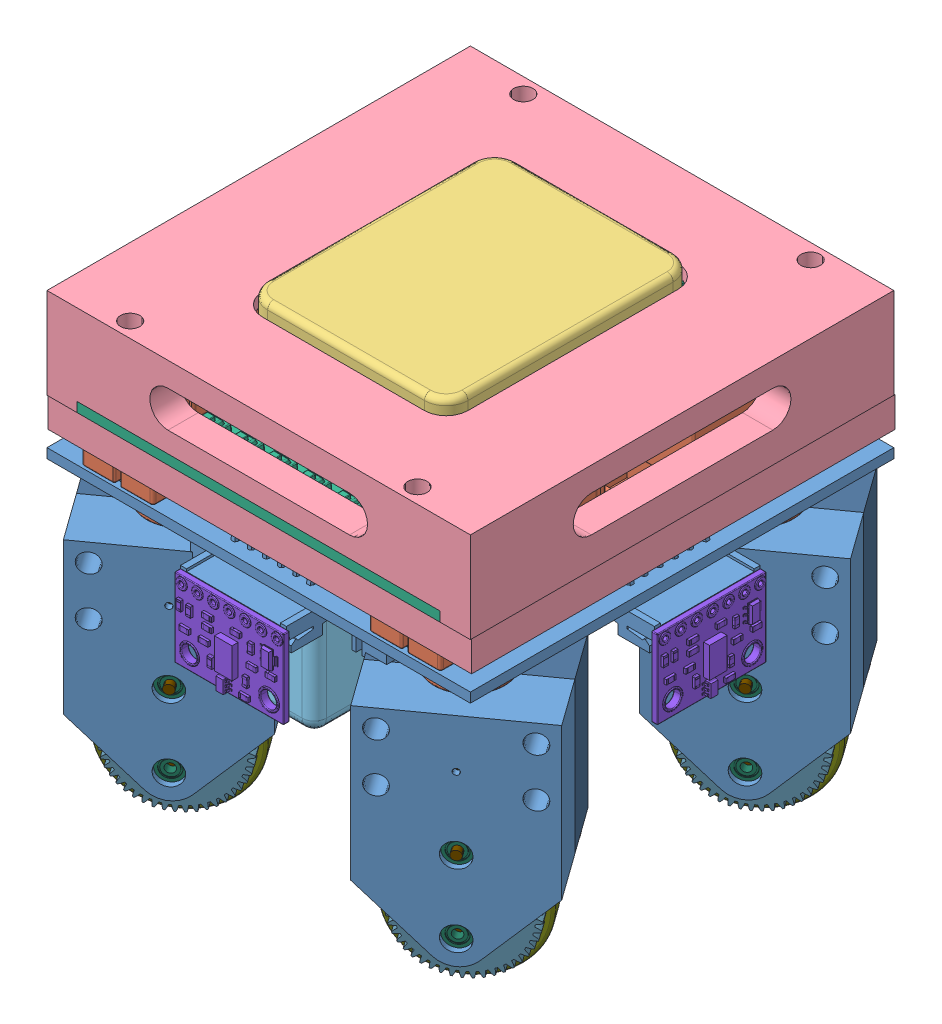
SolidWorks assembly Ver3, configuration Default. Lengths in mm.
Overall size (85.5 79.06 85.23).
91 component instances, 22 part files, 57 mates.
Components (placement in the parent):
- MicroMouse2023_T1-1: MicroMouse2023_T1 [Default] at (98.125 0 -88.375) x (-1 0 0) z (0 -1 0) size (78.34 78.34 13.7)
- Tower Pro MG90S Micro servo.step-1: Tower Pro MG90S Micro servo.step [Default] at (-23.75 9.625 18.55) x (0 0 1) z (1 0 0) size (32.2 32.25 12.33)
- Tower Pro MG90S Micro servo.step-2: Tower Pro MG90S Micro servo.step [Default] at (23.75 9.625 18.55) x (0 0 1) z (1 0 0) size (32.2 32.25 12.33)
- Tower Pro MG90S Micro servo.step-3: Tower Pro MG90S Micro servo.step [Default] at (23.75 9.625 -18.45) x (0 0 -1) z (-1 0 0) size (32.2 32.25 12.33)
- Tower Pro MG90S Micro servo.step-4: Tower Pro MG90S Micro servo.step [Default] at (-23.75 9.625 -18.45) x (0 0 -1) z (-1 0 0) size (32.2 32.25 12.33)
- HMI ESP-1: HMI ESP [Default] at (0 18.5 0) x (0 0 -1) z (1 0 0) size (41.13 12 33.13)
- Nap-1: Nap [Default] at (0 7.5 0) size (70 15 70)
- Pin-3: Pin [Default] at (0 -14.35 0.05) x (0 0 1) z (0 -1 0) size (62 10.5 18.5)
- MicroMouse2023_T2-1: MicroMouse2023_T2 [Default] at (-143.7625 7.5 -93.2) x (1 0 0) z (0 1 0) size (60 70 16.1)
- Ga Pin-1: Ga Pin [Default] at (0 -1.6 0.05) size (60 25 20)
- VL6180X-1: VL6180X [Default] at (-1.3897 -9.4497 22.1675) x (-1 0 0) z (0 0 1) size (18 13 2.15)
- VL6180X-2: VL6180X [Default] at (-22.1675 -9.4497 -1.3897) x (0 0 -1) z (-1 0 0) size (18 13 2.15)
- VL6180X-3: VL6180X [Default] at (1.8897 -9.4497 -22.1675) x (1 0 0) z (0 0 -1) size (18 13 2.15)
- VL6180X-4: VL6180X [Default] at (22.1675 -9.4497 1.8897) x (0 0 1) z (1 0 0) size (18 13 2.15)
- Cum banh _V3-1: Cum banh _V3 [Default] at (23.75 -7.9 23.925) x (0.599967 0 0.800025) z (-0.800025 0 0.599967) size (23.98 46.66 29.51)
  - N20 DC MOTOR Truc dai-1: N20 DC MOTOR Truc dai [Default] at (-12.2958 -8.0501 -0.3318) x (-0.02052 0 0.999789) z (0 1 0) size (12.48 22.6 10.65)
  - Vo SD2_V3-1: Vo SD2_V3 [Default] at (-9.498 -20 -0.1949) x (0.999789 0 0.02052) z (-0.02052 0 0.999789) size (9.5 35.95 25)
  - Nam cham-1: Nam cham [Default] at (-5.4362 -20 -0.5837) x (0.00804 0.92005 -0.39172) z (0.999789 0 0.02052) size (5 5 2)
  - Spur gear 0.4M 15T 1.0N-1: Spur gear 0.4M 15T 1.0N [Default] at (4.0008 -8.0501 0.0027) x (0.999789 0 0.02052) z (-0.020049 -0.213158 0.976812) size (2 6.74 6.78)
  - Banh rang T45-T15-1: Banh rang T45-T15 [Default] at (2.9736 -14.9168 -4.6144) x (0.999789 0 0.02052) z (0.003342 -0.986646 -0.162843) size (4 18.79 18.8)
    - Spur gear 0.4M 15T 1.5N-1: Spur gear 0.4M 15T 1.5N [Default] at (-0.8782 5.44 4.254) size (2 6.74 6.78)
    - Spur gear 0.4M 45T 1.5N-1: Spur gear 0.4M 45T 1.5N [Default] at (1.1218 5.44 4.254) size (2 18.79 18.8)
  - Vong bi 2x5x2.5-1: Vong bi 2x5x2.5 [Default] at (9.6072 -20 0.1972) x (0.020519 -0.01147 -0.999724) z (0.999789 0 0.02052) size (4 4 2)
  - Lop banh xe-1: Lop banh xe [Default] at (2.7494 -31.95 0.0564) x (-0.999789 0 -0.02052) z (0.012413 0.796313 -0.604757) size (4.5 21 21)
  - Mam banh xe-1: Mam banh xe [Default] at (0.4999 -31.95 0.0103) x (-0.999789 0 -0.02052) z (-0.016359 -0.603686 0.797054) size (2 15 15)
  - Spur gear 0.4M 45T 1.5N-1: Spur gear 0.4M 45T 1.5N [Default] at (3.9992 -31.95 0.0821) x (-0.999789 0 -0.02052) z (0.001118 0.998514 -0.054481) size (2 18.79 18.8)
  - Truc 2x20-2: Truc 2x20 [Default] at (0 -31.95 0) x (0.017704 -0.505658 -0.862552) z (0.999789 0 0.02052) size (1.5 1.5 14)
  - Vo SD1_V3-1: Vo SD1_V3 [Default] at (0 -20 0) x (0.999789 0 0.02052) z (-0.02052 0 0.999789) size (9.5 35.95 25)
  - Vong bi 2x5x2.5-2: Vong bi 2x5x2.5 [Default] at (-5.3897 -31.95 -0.1106) x (0.002111 0.994694 -0.102859) z (0.999789 0 0.02052) size (4 4 2)
  - Vong bi 2x5x2.5-3: Vong bi 2x5x2.5 [Default] at (9.6072 -31.95 0.1972) x (0.02052 0 -0.999789) z (0.999789 0 0.02052) size (4 4 2)
  - MT6701-1: MT6701 [Default] at (-11.0547 -20 -0.2269) x (0.02052 0 -0.999789) z (0.999789 0 0.02052) size (23 17 3.61)
  - Truc 2x20-3: Truc 2x20 [Default] at (2.5524 -20 0.0524) x (0.009005 -0.898579 -0.43872) z (0.999789 0 0.02052) size (1.5 1.5 14)
  - Ga nam chamV3-1: Ga nam chamV3 [Default] at (-2.4465 -20 -0.0502) x (-0.999789 0 -0.02052) z (0.019076 -0.368528 -0.929421) size (4 8 8)
- Cum banh _V3-2: Cum banh _V3 [Default] at (-23.75 -7.9 23.925) x (0.599967 0 0.800025) z (-0.800025 0 0.599967) size (23.98 46.66 29.51)
  - N20 DC MOTOR Truc dai-1: N20 DC MOTOR Truc dai [Default] at (-12.2958 -8.0501 -0.3318) x (-0.02052 0 0.999789) z (0 1 0) size (12.48 22.6 10.65)
  - Vo SD2_V3-1: Vo SD2_V3 [Default] at (-9.498 -20 -0.1949) x (0.999789 0 0.02052) z (-0.02052 0 0.999789) size (9.5 35.95 25)
  - Nam cham-1: Nam cham [Default] at (-5.4362 -20 -0.5837) x (0.00804 0.92005 -0.39172) z (0.999789 0 0.02052) size (5 5 2)
  - Spur gear 0.4M 15T 1.0N-1: Spur gear 0.4M 15T 1.0N [Default] at (4.0008 -8.0501 0.0027) x (0.999789 0 0.02052) z (-0.020049 -0.213158 0.976812) size (2 6.74 6.78)
  - Banh rang T45-T15-1: Banh rang T45-T15 [Default] at (2.9736 -14.9168 -4.6144) x (0.999789 0 0.02052) z (0.003342 -0.986646 -0.162843) size (4 18.79 18.8)
    - Spur gear 0.4M 15T 1.5N-1: Spur gear 0.4M 15T 1.5N [Default] at (-0.8782 5.44 4.254) size (2 6.74 6.78)
    - Spur gear 0.4M 45T 1.5N-1: Spur gear 0.4M 45T 1.5N [Default] at (1.1218 5.44 4.254) size (2 18.79 18.8)
  - Vong bi 2x5x2.5-1: Vong bi 2x5x2.5 [Default] at (9.6072 -20 0.1972) x (0.020519 -0.01147 -0.999724) z (0.999789 0 0.02052) size (4 4 2)
  - Lop banh xe-1: Lop banh xe [Default] at (2.7494 -31.95 0.0564) x (-0.999789 0 -0.02052) z (0.012413 0.796313 -0.604757) size (4.5 21 21)
  - Mam banh xe-1: Mam banh xe [Default] at (0.4999 -31.95 0.0103) x (-0.999789 0 -0.02052) z (-0.016359 -0.603686 0.797054) size (2 15 15)
  - Spur gear 0.4M 45T 1.5N-1: Spur gear 0.4M 45T 1.5N [Default] at (3.9992 -31.95 0.0821) x (-0.999789 0 -0.02052) z (0.001118 0.998514 -0.054481) size (2 18.79 18.8)
  - Truc 2x20-2: Truc 2x20 [Default] at (0 -31.95 0) x (0.017704 -0.505658 -0.862552) z (0.999789 0 0.02052) size (1.5 1.5 14)
  - Vo SD1_V3-1: Vo SD1_V3 [Default] at (0 -20 0) x (0.999789 0 0.02052) z (-0.02052 0 0.999789) size (9.5 35.95 25)
  - Vong bi 2x5x2.5-2: Vong bi 2x5x2.5 [Default] at (-5.3897 -31.95 -0.1106) x (0.002111 0.994694 -0.102859) z (0.999789 0 0.02052) size (4 4 2)
  - Vong bi 2x5x2.5-3: Vong bi 2x5x2.5 [Default] at (9.6072 -31.95 0.1972) x (0.02052 0 -0.999789) z (0.999789 0 0.02052) size (4 4 2)
  - MT6701-1: MT6701 [Default] at (-11.0547 -20 -0.2269) x (0.02052 0 -0.999789) z (0.999789 0 0.02052) size (23 17 3.61)
  - Truc 2x20-3: Truc 2x20 [Default] at (2.5524 -20 0.0524) x (0.009005 -0.898579 -0.43872) z (0.999789 0 0.02052) size (1.5 1.5 14)
  - Ga nam chamV3-1: Ga nam chamV3 [Default] at (-2.4465 -20 -0.0502) x (-0.999789 0 -0.02052) z (0.019076 -0.368528 -0.929421) size (4 8 8)
- Cum banh _V3-3: Cum banh _V3 [Default] at (23.75 -7.9 -23.825) x (0.599967 0 0.800025) z (-0.800025 0 0.599967) size (23.98 46.66 29.51)
  - N20 DC MOTOR Truc dai-1: N20 DC MOTOR Truc dai [Default] at (-12.2958 -8.0501 -0.3318) x (-0.02052 0 0.999789) z (0 1 0) size (12.48 22.6 10.65)
  - Vo SD2_V3-1: Vo SD2_V3 [Default] at (-9.498 -20 -0.1949) x (0.999789 0 0.02052) z (-0.02052 0 0.999789) size (9.5 35.95 25)
  - Nam cham-1: Nam cham [Default] at (-5.4362 -20 -0.5837) x (0.00804 0.92005 -0.39172) z (0.999789 0 0.02052) size (5 5 2)
  - Spur gear 0.4M 15T 1.0N-1: Spur gear 0.4M 15T 1.0N [Default] at (4.0008 -8.0501 0.0027) x (0.999789 0 0.02052) z (-0.020049 -0.213158 0.976812) size (2 6.74 6.78)
  - Banh rang T45-T15-1: Banh rang T45-T15 [Default] at (2.9736 -14.9168 -4.6144) x (0.999789 0 0.02052) z (0.003342 -0.986646 -0.162843) size (4 18.79 18.8)
    - Spur gear 0.4M 15T 1.5N-1: Spur gear 0.4M 15T 1.5N [Default] at (-0.8782 5.44 4.254) size (2 6.74 6.78)
    - Spur gear 0.4M 45T 1.5N-1: Spur gear 0.4M 45T 1.5N [Default] at (1.1218 5.44 4.254) size (2 18.79 18.8)
  - Vong bi 2x5x2.5-1: Vong bi 2x5x2.5 [Default] at (9.6072 -20 0.1972) x (0.020519 -0.01147 -0.999724) z (0.999789 0 0.02052) size (4 4 2)
  - Lop banh xe-1: Lop banh xe [Default] at (2.7494 -31.95 0.0564) x (-0.999789 0 -0.02052) z (0.012413 0.796313 -0.604757) size (4.5 21 21)
  - Mam banh xe-1: Mam banh xe [Default] at (0.4999 -31.95 0.0103) x (-0.999789 0 -0.02052) z (-0.016359 -0.603686 0.797054) size (2 15 15)
  - Spur gear 0.4M 45T 1.5N-1: Spur gear 0.4M 45T 1.5N [Default] at (3.9992 -31.95 0.0821) x (-0.999789 0 -0.02052) z (0.001118 0.998514 -0.054481) size (2 18.79 18.8)
  - Truc 2x20-2: Truc 2x20 [Default] at (0 -31.95 0) x (0.017704 -0.505658 -0.862552) z (0.999789 0 0.02052) size (1.5 1.5 14)
  - Vo SD1_V3-1: Vo SD1_V3 [Default] at (0 -20 0) x (0.999789 0 0.02052) z (-0.02052 0 0.999789) size (9.5 35.95 25)
  - Vong bi 2x5x2.5-2: Vong bi 2x5x2.5 [Default] at (-5.3897 -31.95 -0.1106) x (0.002111 0.994694 -0.102859) z (0.999789 0 0.02052) size (4 4 2)
  - Vong bi 2x5x2.5-3: Vong bi 2x5x2.5 [Default] at (9.6072 -31.95 0.1972) x (0.02052 0 -0.999789) z (0.999789 0 0.02052) size (4 4 2)
  - MT6701-1: MT6701 [Default] at (-11.0547 -20 -0.2269) x (0.02052 0 -0.999789) z (0.999789 0 0.02052) size (23 17 3.61)
  - Truc 2x20-3: Truc 2x20 [Default] at (2.5524 -20 0.0524) x (0.009005 -0.898579 -0.43872) z (0.999789 0 0.02052) size (1.5 1.5 14)
  - Ga nam chamV3-1: Ga nam chamV3 [Default] at (-2.4465 -20 -0.0502) x (-0.999789 0 -0.02052) z (0.019076 -0.368528 -0.929421) size (4 8 8)
- Cum banh _V3-4: Cum banh _V3 [Default] at (-23.75 -7.9 -23.825) x (0.599967 0 0.800025) z (-0.800025 0 0.599967) size (23.98 46.66 29.51)
  - N20 DC MOTOR Truc dai-1: N20 DC MOTOR Truc dai [Default] at (-12.2958 -8.0501 -0.3318) x (-0.02052 0 0.999789) z (0 1 0) size (12.48 22.6 10.65)
  - Vo SD2_V3-1: Vo SD2_V3 [Default] at (-9.498 -20 -0.1949) x (0.999789 0 0.02052) z (-0.02052 0 0.999789) size (9.5 35.95 25)
  - Nam cham-1: Nam cham [Default] at (-5.4362 -20 -0.5837) x (0.00804 0.92005 -0.39172) z (0.999789 0 0.02052) size (5 5 2)
  - Spur gear 0.4M 15T 1.0N-1: Spur gear 0.4M 15T 1.0N [Default] at (4.0008 -8.0501 0.0027) x (0.999789 0 0.02052) z (-0.020049 -0.213158 0.976812) size (2 6.74 6.78)
  - Banh rang T45-T15-1: Banh rang T45-T15 [Default] at (2.9736 -14.9168 -4.6144) x (0.999789 0 0.02052) z (0.003342 -0.986646 -0.162843) size (4 18.79 18.8)
    - Spur gear 0.4M 15T 1.5N-1: Spur gear 0.4M 15T 1.5N [Default] at (-0.8782 5.44 4.254) size (2 6.74 6.78)
    - Spur gear 0.4M 45T 1.5N-1: Spur gear 0.4M 45T 1.5N [Default] at (1.1218 5.44 4.254) size (2 18.79 18.8)
  - Vong bi 2x5x2.5-1: Vong bi 2x5x2.5 [Default] at (9.6072 -20 0.1972) x (0.020519 -0.01147 -0.999724) z (0.999789 0 0.02052) size (4 4 2)
  - Lop banh xe-1: Lop banh xe [Default] at (2.7494 -31.95 0.0564) x (-0.999789 0 -0.02052) z (0.012413 0.796313 -0.604757) size (4.5 21 21)
  - Mam banh xe-1: Mam banh xe [Default] at (0.4999 -31.95 0.0103) x (-0.999789 0 -0.02052) z (-0.016359 -0.603686 0.797054) size (2 15 15)
  - Spur gear 0.4M 45T 1.5N-1: Spur gear 0.4M 45T 1.5N [Default] at (3.9992 -31.95 0.0821) x (-0.999789 0 -0.02052) z (0.001118 0.998514 -0.054481) size (2 18.79 18.8)
  - Truc 2x20-2: Truc 2x20 [Default] at (0 -31.95 0) x (0.017704 -0.505658 -0.862552) z (0.999789 0 0.02052) size (1.5 1.5 14)
  - Vo SD1_V3-1: Vo SD1_V3 [Default] at (0 -20 0) x (0.999789 0 0.02052) z (-0.02052 0 0.999789) size (9.5 35.95 25)
  - Vong bi 2x5x2.5-2: Vong bi 2x5x2.5 [Default] at (-5.3897 -31.95 -0.1106) x (0.002111 0.994694 -0.102859) z (0.999789 0 0.02052) size (4 4 2)
  - Vong bi 2x5x2.5-3: Vong bi 2x5x2.5 [Default] at (9.6072 -31.95 0.1972) x (0.02052 0 -0.999789) z (0.999789 0 0.02052) size (4 4 2)
  - MT6701-1: MT6701 [Default] at (-11.0547 -20 -0.2269) x (0.02052 0 -0.999789) z (0.999789 0 0.02052) size (23 17 3.61)
  - Truc 2x20-3: Truc 2x20 [Default] at (2.5524 -20 0.0524) x (0.009005 -0.898579 -0.43872) z (0.999789 0 0.02052) size (1.5 1.5 14)
  - Ga nam chamV3-1: Ga nam chamV3 [Default] at (-2.4465 -20 -0.0502) x (-0.999789 0 -0.02052) z (0.019076 -0.368528 -0.929421) size (4 8 8)
- khung dem-1: khung dem [Default] at (0 5 -0.2) size (70 5 70)
Mates (geometry in assembly coordinates):
- Coincident1: coincident aligned: plane of MicroMouse2023_T1-1 through (98.125 0 -88.375) normal (0 1 0)
- Coincident2: coincident: point of MicroMouse2023_T1-1
- Coincident3: coincident: unknown of MicroMouse2023_T1-1
- Coincident4: coincident: unknown of MicroMouse2023_T1-1
- Concentric1: concentric anti-aligned: cylinder of MicroMouse2023_T1-1 through (-23.75 0 32.3) axis (0 1 0) radius 1.55; cylinder of Tower Pro MG90S Micro servo.step-1 through (-23.75 20.9 32.3) axis (0 -1 0) radius 1.25
- Concentric2: concentric anti-aligned: cylinder of MicroMouse2023_T1-1 through (-23.75 0 4.8) axis (0 1 0) radius 1.55; cylinder of Tower Pro MG90S Micro servo.step-1 through (-23.75 20.9 4.8) axis (0 -1 0) radius 1.25
- Concentric3: concentric anti-aligned: cylinder of MicroMouse2023_T1-1 through (-23.75 0 -4.7) axis (0 1 0) radius 1.55; cylinder of Tower Pro MG90S Micro servo.step-4 through (-23.75 20.9 -4.7) axis (0 -1 0) radius 1.25
- Concentric4: concentric anti-aligned: cylinder of MicroMouse2023_T1-1 through (-23.75 0 -32.2) axis (0 1 0) radius 1.55; cylinder of Tower Pro MG90S Micro servo.step-4 through (-23.75 20.9 -32.2) axis (0 -1 0) radius 1.25
- Concentric5: concentric anti-aligned: cylinder of MicroMouse2023_T1-1 through (23.75 0 32.3) axis (0 1 0) radius 1.55; cylinder of Tower Pro MG90S Micro servo.step-2 through (23.75 20.9 32.3) axis (0 -1 0) radius 1.25
- Concentric6: concentric anti-aligned: cylinder of MicroMouse2023_T1-1 through (23.75 0 -4.7) axis (0 1 0) radius 1.55; cylinder of Tower Pro MG90S Micro servo.step-3 through (23.75 20.9 -4.7) axis (0 -1 0) radius 1.25
- Concentric7: concentric anti-aligned: cylinder of MicroMouse2023_T1-1 through (23.75 0 -32.2) axis (0 1 0) radius 1.55; cylinder of Tower Pro MG90S Micro servo.step-3 through (23.75 20.9 -32.2) axis (0 -1 0) radius 1.25
- Concentric8: concentric anti-aligned: cylinder of MicroMouse2023_T1-1 through (23.75 0 4.8) axis (0 1 0) radius 1.55; cylinder of Tower Pro MG90S Micro servo.step-2 through (23.75 20.9 4.8) axis (0 -1 0) radius 1.25
- Coincident5: coincident anti-aligned: plane of MicroMouse2023_T1-1 through (98.125 0 -88.375) normal (0 1 0); plane of Tower Pro MG90S Micro servo.step-2 through (23.75 0 18.55) normal (0 -1 0)
- Coincident6: coincident anti-aligned: plane of MicroMouse2023_T1-1 through (98.125 0 -88.375) normal (0 1 0); plane of Tower Pro MG90S Micro servo.step-3 through (23.75 0 -18.45) normal (0 -1 0)
- Coincident7: coincident anti-aligned: plane of MicroMouse2023_T1-1 through (98.125 0 -88.375) normal (0 1 0); plane of Tower Pro MG90S Micro servo.step-4 through (-23.75 0 -18.45) normal (0 -1 0)
- Coincident8: coincident anti-aligned: plane of MicroMouse2023_T1-1 through (98.125 0 -88.375) normal (0 1 0); plane of Tower Pro MG90S Micro servo.step-1 through (-23.75 0 18.55) normal (0 -1 0)
- Coincident14: coincident aligned: plane of MicroMouse2023_T1-1 through (-35 0 -35) normal (-1 0 0); plane of Nap-1 through (-35 22.5 35) normal (-1 0 0)
- Coincident15: coincident aligned: plane of MicroMouse2023_T1-1 through (35 0 -35) normal (0 0 -1); plane of Nap-1 through (-35 22.5 -35) normal (0 0 -1)
- Distance5: distance = 2 mm aligned: plane of HMI ESP-1 through (12.965 24.5 -16.965) normal (0 1 0); plane of Nap-1 through (0 22.5 0) normal (0 1 0)
- Width1: width anti-aligned: plane of Nap-1 through (17 25.5 0) normal (-1 0 0); plane of HMI ESP-1 through (-17 25.5 0) normal (1 0 0); plane of Nap-1 through (16.565 24.5 16.965) normal (1 0 0); plane of HMI ESP-1 through (-16.565 24.5 16.965) normal (-1 0 0)
- Width2: width anti-aligned: plane of HMI ESP-1 through (12.965 24.5 -20.565) normal (0 0 -1); plane of Nap-1 through (12.965 24.5 20.565) normal (0 0 1); plane of HMI ESP-1 through (0 25.5 -21) normal (0 0 1); plane of Nap-1 through (0 25.5 21) normal (0 0 -1)
- Coincident21: coincident aligned: plane of Nap-1 through (-35 22.5 35) normal (0 0 1); plane of MicroMouse2023_T2-1 through (30 7.5 35) normal (0 0 1)
- Coincident22: coincident anti-aligned: plane of Nap-1 through (-30 22.5 30) normal (1 0 0); plane of MicroMouse2023_T2-1 through (-30 7.5 35) normal (-1 0 0)
- Concentric15: concentric aligned: cylinder of MicroMouse2023_T1-1 through (-23.75 0 -4.7) axis (0 1 0) radius 1.55; cylinder of Ga Pin-1 through (-23.75 -7.6 -4.7) axis (0 1 0) radius 2
- Concentric16: concentric aligned: cylinder of MicroMouse2023_T1-1 through (-23.75 0 4.8) axis (0 1 0) radius 1.55; cylinder of Ga Pin-1 through (-23.75 -7.6 4.8) axis (0 1 0) radius 2
- Coincident23: coincident anti-aligned: plane of Pin-3 through (5.25 -14.35 0.05) normal (1 0 0); plane of Ga Pin-1 through (5.25 -6.6 10.05) normal (-1 0 0)
- Coincident24: coincident anti-aligned: plane of Pin-3 through (-5.25 -23.6 -30.95) normal (0 -1 0); plane of Ga Pin-1 through (-5.25 -23.6 10.05) normal (0 1 0)
- Width4: width anti-aligned: plane of Ga Pin-1 through (0 -1.6 -9.95) normal (0 0 -1); plane of Pin-3 through (0 -1.6 10.05) normal (0 0 1); plane of Ga Pin-1 through (-5.25 -5.1 31.05) normal (0 0 1); plane of Pin-3 through (-5.25 -5.1 -30.95) normal (0 0 -1)
- Coincident25: coincident anti-aligned: plane of MicroMouse2023_T1-1 through (98.125 -1.6 -88.375) normal (0 -1 0); plane of Ga Pin-1 through (-30 -1.6 10.05) normal (0 1 0)
- Coincident26: coincident aligned: plane of MicroMouse2023_T1-1 through (8.75 -2.05 33.1675) normal (0 1 0); plane of VL6180X-1 through (9.25 -2.05 40.1675) normal (0 1 0)
- Coincident27: coincident anti-aligned: plane of MicroMouse2023_T1-1 through (0 -2.433 39.1675) normal (0 0 1); plane of VL6180X-1 through (0.25 -8.55 39.1675) normal (0 0 -1)
- Coincident28: coincident aligned: plane of MicroMouse2023_T1-1 through (-8.75 -3.655 35.4393) normal (-1 0 0); plane of VL6180X-1 through (-8.75 -15.05 40.1675) normal (-1 0 0)
- Coincident30: coincident anti-aligned: plane of MicroMouse2023_T1-1 through (-39.1675 -2.433 0) normal (-1 0 0); plane of VL6180X-2 through (-39.1675 -8.55 0.25) normal (1 0 0)
- Coincident31: coincident aligned: plane of MicroMouse2023_T1-1 through (-33.1675 -2.05 8.75) normal (0 1 0); plane of VL6180X-2 through (-40.1675 -2.05 9.25) normal (0 1 0)
- Coincident32: coincident aligned: plane of MicroMouse2023_T1-1 through (-35.4393 -3.655 -8.75) normal (0 0 -1); plane of VL6180X-2 through (-40.1675 -15.05 -8.75) normal (0 0 -1)
- Coincident33: coincident anti-aligned: plane of MicroMouse2023_T1-1 through (0 -2.433 -39.1675) normal (0 0 -1); plane of VL6180X-3 through (0.25 -8.55 -39.1675) normal (0 0 1)
- Coincident34: coincident aligned: plane of MicroMouse2023_T1-1 through (-8.75 -2.05 -33.1675) normal (0 1 0); plane of VL6180X-3 through (-8.75 -2.05 -40.1675) normal (0 1 0)
- Coincident35: coincident aligned: plane of MicroMouse2023_T1-1 through (-8.75 -3.655 -35.4393) normal (-1 0 0); plane of VL6180X-3 through (-8.75 -15.05 -40.1675) normal (-1 0 0)
- Coincident36: coincident anti-aligned: plane of MicroMouse2023_T1-1 through (39.1675 -2.433 0) normal (1 0 0); plane of VL6180X-4 through (39.1675 -8.55 0.25) normal (-1 0 0)
- Coincident37: coincident aligned: plane of MicroMouse2023_T1-1 through (33.1675 -2.05 -8.75) normal (0 1 0); plane of VL6180X-4 through (40.1675 -2.05 -8.75) normal (0 1 0)
- Coincident38: coincident aligned: plane of MicroMouse2023_T1-1 through (35.4393 -3.655 -8.75) normal (0 0 -1); plane of VL6180X-4 through (40.1675 -15.05 -8.75) normal (0 0 -1)
- Concentric56: concentric anti-aligned: cylinder of Tower Pro MG90S Micro servo.step-2 through (23.75 -7.9 23.925) axis (0 1 0) radius 1.7; cylinder of Cum banh _V3-1/Vo SD2_V3-1 through (23.75 -3.95 23.925) axis (0 -1 0) radius 2.25
- Concentric58: concentric anti-aligned: cylinder of Tower Pro MG90S Micro servo.step-3 through (23.75 -7.9 -23.825) axis (0 1 0) radius 1.7; cylinder of Cum banh _V3-3/Vo SD2_V3-1 through (23.75 -3.95 -23.825) axis (0 -1 0) radius 2.25
- Concentric59: concentric anti-aligned: cylinder of Tower Pro MG90S Micro servo.step-4 through (-23.75 -7.9 -23.825) axis (0 1 0) radius 1.7; cylinder of Cum banh _V3-4/Vo SD2_V3-1 through (-23.75 -3.95 -23.825) axis (0 -1 0) radius 2.25
- Concentric60: concentric aligned: cylinder of Tower Pro MG90S Micro servo.step-1 through (-23.75 -7.9 23.925) axis (0 1 0) radius 1.7; cylinder of Cum banh _V3-2/Vo SD1_V3-1 through (-23.75 -13.9 23.925) axis (0 1 0) radius 2.25
- Coincident81: coincident aligned: circle of Tower Pro MG90S Micro servo.step-2; plane of Cum banh _V3-1/Vo SD2_V3-1 through (23.75 -7.9 23.925) normal (0 1 0)
- Coincident82: coincident anti-aligned: circle of Tower Pro MG90S Micro servo.step-1; plane of Cum banh _V3-2/Vo SD2_V3-1 through (-23.75 -7.9 23.925) normal (0 1 0)
- Coincident83: coincident anti-aligned: circle of Tower Pro MG90S Micro servo.step-1; plane of Cum banh _V3-4/Vo SD2_V3-1 through (-23.75 -7.9 -23.825) normal (0 1 0)
- Coincident84: coincident anti-aligned: circle of Tower Pro MG90S Micro servo.step-1; plane of Cum banh _V3-3/Vo SD1_V3-1 through (29.2925 -7.9 -16.1094) normal (0 1 0)
- Parallel1: parallel aligned: plane of Cum banh _V3-3/MT6701-1 through (17.2991 -27.9 -32.8052) normal (-0.583423 0 -0.812168); plane of Cum banh _V3-4/MT6701-1 through (-30.2009 -27.9 -32.8052) normal (-0.583423 0 -0.812168)
- Parallel2: parallel aligned: plane of Cum banh _V3-3/MT6701-1 through (17.2991 -27.9 -32.8052) normal (-0.583423 0 -0.812168); plane of Cum banh _V3-2/MT6701-1 through (-30.2009 -27.9 14.9448) normal (-0.583423 0 -0.812168)
- Parallel3: parallel aligned: plane of Cum banh _V3-3/MT6701-1 through (17.2991 -27.9 -32.8052) normal (-0.583423 0 -0.812168); plane of Cum banh _V3-1/MT6701-1 through (17.2991 -27.9 14.9448) normal (-0.583423 0 -0.812168)
- Concentric61: concentric aligned: cylinder of Tower Pro MG90S Micro servo.step-1 through (-23.75 20.9 32.3) axis (0 -1 0) radius 1.25; cylinder of khung dem-1 through (-23.75 7.5 32.3) axis (0 -1 0) radius 1.6
- Concentric62: concentric aligned: cylinder of Tower Pro MG90S Micro servo.step-2 through (23.75 20.9 32.3) axis (0 -1 0) radius 1.25; cylinder of khung dem-1 through (23.75 7.5 32.3) axis (0 -1 0) radius 1.6
- Coincident85: coincident anti-aligned: plane of Tower Pro MG90S Micro servo.step-2 through (23.75 2.5 18.55) normal (0 1 0); plane of khung dem-1 through (0 2.5 -0.2) normal (0 -1 0)
- Coincident86: coincident anti-aligned: plane of MicroMouse2023_T2-1 through (-143.7625 7.5 -93.2) normal (0 -1 0); plane of khung dem-1 through (0 7.5 -0.2) normal (0 1 0)
- Coincident87: coincident anti-aligned: plane of Nap-1 through (0 9.1 0) normal (0 -1 0); plane of MicroMouse2023_T2-1 through (-143.7625 9.1 -93.2) normal (0 1 0)
